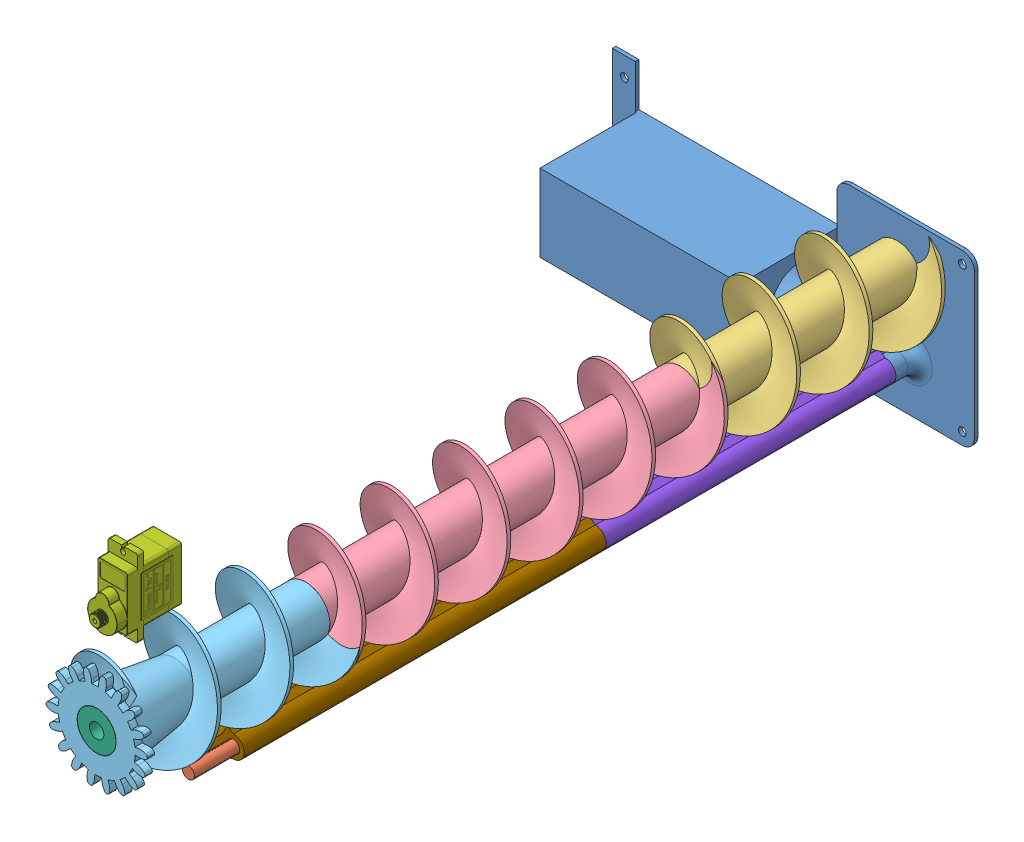
SolidWorks assembly Assemblage système de remontée des cerises, configuration Défaut. Lengths in mm.
Overall size (150 120.23 360).
13 component instances, 10 part files, 12 mates.
Components (placement in the parent):
- Support vis base-1: Support vis base [Défaut] at (-74.3603 40.3487 129.25) size (150 70 41.5)
- Tige de guidage-1: Tige de guidage [Défaut] at (18.6397 -13.6513 130.75) x (0.90567 0.423983 0) z (0 0 1) size (5 5 298.65)
- Tige de guidage-2: Tige de guidage [Défaut] at (38.6397 -8.6513 130.75) x (-0.010885 -0.999941 0) z (0 0 1) size (5 5 298.65)
- Assemblage Vis Roulement Engrenage-1: Assemblage Vis Roulement Engrenage [Défaut] at (25.2291 26.0541 645.75) x (-0.533421 0.84585 0) z (0 0 -1) size (45.32 45.12 360)
  - P1 vis sans fin-1: P1 vis sans fin [Défaut] at (-9.3123 4.0708 180) size (45.32 45.12 360)
  - P2 vis sans fin-1: P2 vis sans fin [Défaut] at (-9.3123 4.0708 180) size (45.32 45.12 360)
  - P3 vis sans fin V.2-1: P3 vis sans fin V.2 [Défaut] at (-9.3123 4.0708 180) size (45.32 45.05 360)
  - Roulement à bille-1: Roulement à bille [Défaut] at (-9.3123 4.0708 183.35) x (0.90497 0.425475 0) z (0 0 1) size (16 16 5)
  - Roulement à bille-2: Roulement à bille [Défaut] at (-9.3123 4.0708 510) x (0.936021 -0.351945 0) z (0 0 1) size (16 16 5)
- SG90 Servo-1: SG90 Servo [Défaut] at (5.9315 58.5755 427.1322) x (0 1 0) z (1 0 0) size (32.1 29.95 12.4)
- Engrenage vis sans fin-2: Engrenage vis sans fin [Défaut] at (33.7147 60.0987 460.15) x (0.883908 0.46766 0) z (0 0 1) size (45.1 45.1 12.5)
- Guidage remontée 2-1: Guidage remontée 2 [Défaut] at (18.6397 -13.6513 140.75) x (0 1 0) z (0 0 1) size (26.04 33.73 120)
- Guidage remontée-2: Guidage remontée [Défaut] at (18.6397 -13.6513 260.75) x (0 1 0) z (0 0 1) size (26.04 33.73 150)
Mates (geometry in assembly coordinates):
- Coaxiale3: concentric aligned: cylinder of Support vis base-1 through (18.6397 -13.6513 140.75) axis (0 0 -1) radius 2.6; cylinder of Tige de guidage-1 through (18.6397 -13.6513 429.4) axis (0 0 -1) radius 2.5
- Coaxiale4: concentric aligned: cylinder of Support vis base-1 through (38.6397 -8.6513 140.75) axis (0 0 -1) radius 2.6; cylinder of Tige de guidage-2 through (38.6397 -8.6513 429.4) axis (0 0 -1) radius 2.5
- Coïncidente1: coincident anti-aligned: plane of Support vis base-1 through (-74.3603 40.3487 130.75) normal (0 0 1); plane of Tige de guidage-2 through (38.6397 -8.6513 130.75) normal (0 0 -1)
- Coïncidente2: coincident anti-aligned: plane of Support vis base-1 through (-74.3603 40.3487 130.75) normal (0 0 1); plane of Tige de guidage-1 through (18.6397 -13.6513 130.75) normal (0 0 -1)
- Coaxiale5: concentric anti-aligned: cylinder of Support vis base-1 through (33.6397 20.3487 135.75) axis (0 0 -1) radius 2.5; cylinder of Assemblage Vis Roulement Engrenage-1/Roulement à bille-2 through (33.6397 20.3487 130.75) axis (0 0 1) radius 3
- Coïncidente3: coincident anti-aligned: plane of Support vis base-1 through (-74.3603 40.3487 130.75) normal (0 0 1); plane of Assemblage Vis Roulement Engrenage-1/Roulement à bille-2 through (33.6397 20.3487 130.75) normal (0 0 -1)
- Coïncidente9: coincident anti-aligned: plane of SG90 Servo-1 through (33.7147 60.0987 460.15) normal (0 0 1); plane of Engrenage vis sans fin-2 through (33.7147 60.0987 460.15) normal (0 0 -1)
- Coaxiale8: concentric aligned: circle of Support vis base-1; circle of Guidage remontée-1
- Coïncidente10: coincident anti-aligned: plane of Support vis base-1 through (38.6397 -8.6513 140.75) normal (0 0 1); plane of Guidage remontée-1 through (18.6397 -13.6513 140.75) normal (0 0 -1)
- Coaxiale9: concentric aligned: circle of Support vis base-1; circle of Guidage remontée-1
- Coïncidente11: coincident aligned: circle of Guidage remontée 2-1; circle of Guidage remontée-2
- Coïncidente12: coincident aligned: circle of Guidage remontée 2-1; circle of Guidage remontée-2
